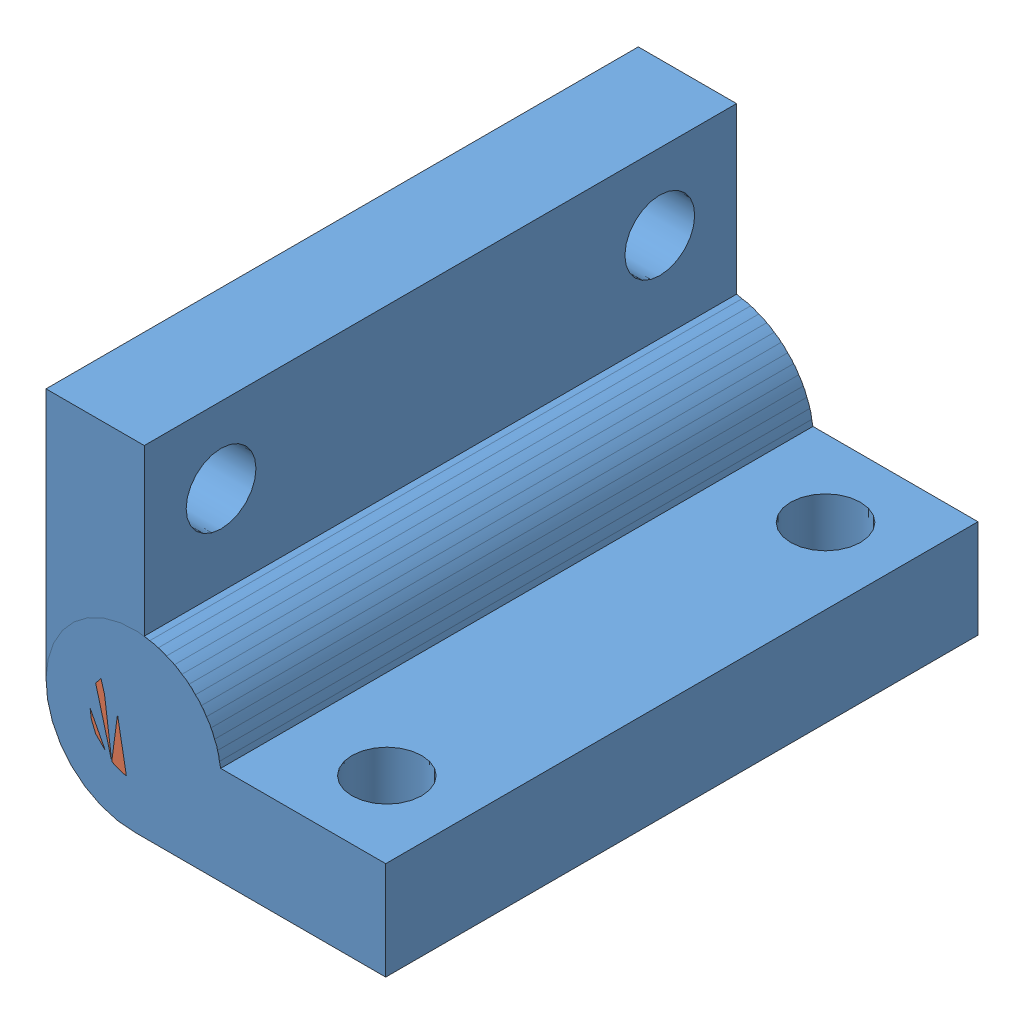
SolidWorks assembly hinge_big, configuration Default. Lengths in mm.
Overall size (24.58 24.58 42.86).
3 component instances, 2 part files, 4 mates.
Components (placement in the parent):
- hinge1-1: hinge1 [Default] at (11.1163 -32.4356 -20.0726) size (24.58 12.68 42.86)
- rod-1: rod [Default] at (-8.0334 -0.372 -20.0726) size (6.35 6.35 42.86)
- hinge1-2: hinge1 [Default] at (-40.1006 18.7717 22.7899) x (-0.000186 1 0) z (0 0 -1) size (24.58 12.68 42.86)
Mates (geometry in assembly coordinates):
- Concentric1: concentric anti-aligned: circle of hinge1-1; cylinder of rod-1 through (-8.0334 -0.372 22.7899) axis (0 0 -1) radius 3.175
- Coincident1: coincident aligned: plane of hinge1-1 through (-8.0334 -0.372 22.7899) normal (0 0 1); plane of rod-1 through (-8.0334 -0.372 22.7899) normal (0 0 1)
- Concentric2: concentric anti-aligned: circle of rod-1; circle of hinge1-2
- Coincident2: coincident aligned: plane of hinge1-1 through (-8.0334 -0.372 22.7899) normal (0 0 1); plane of hinge1-2 through (-8.0334 -0.372 22.7899) normal (0 0 1)
